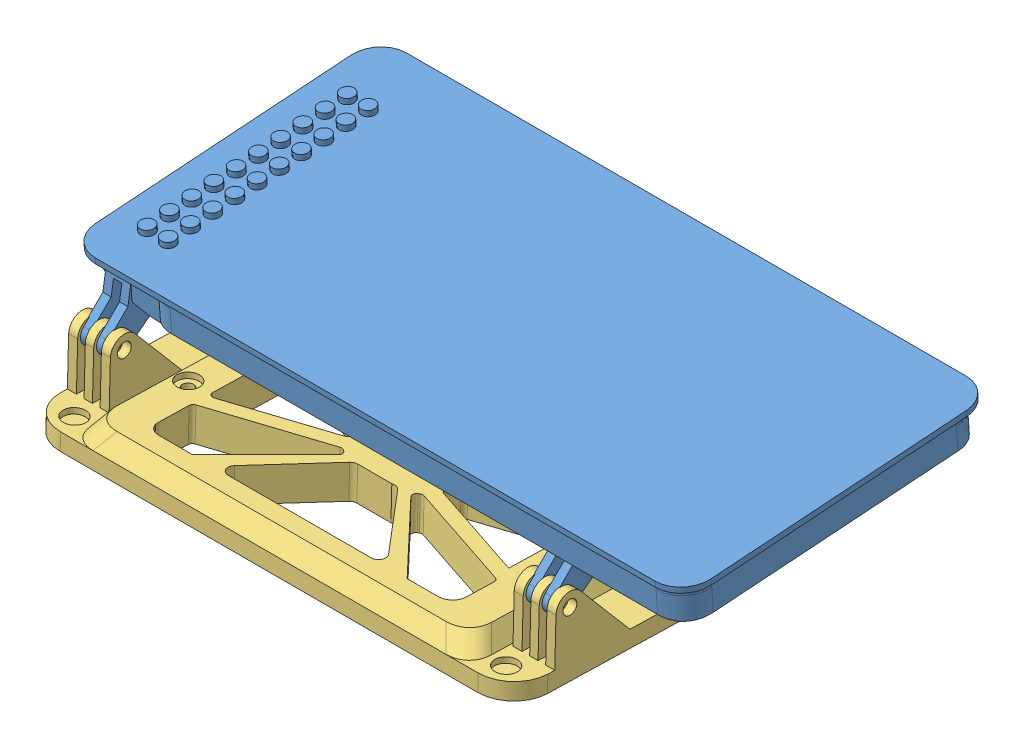
SolidWorks assembly Pi Screen Assembly, configuration Default. Lengths in mm.
Overall size (221 61.76 131.08).
3 component instances, 3 part files, 7 mates.
Components (placement in the parent):
- Pi Touch Screen-1: Pi Touch Screen [Default] at (61.75 84.4571 107.2044) x (1 0 0) z (0 0.997511 0.070505) size (221 114.52 33.01)
- User Library-Raspberry Pi 3-2-1: User Library-Raspberry Pi 3-2 [Default] at (-18.5338 72.6927 106.2834) x (-1 0 0) z (0 -0.997511 -0.070505) size (89.64 57.31 18.59)
- Raspberry Pi case-1: Raspberry Pi case [Default] at (29.5 34.9078 131.6046) x (1 0 0) z (0 0.999657 -0.026177) size (175 98 28)
Mates (geometry in assembly coordinates):
- Concentric1: concentric anti-aligned: cylinder of Pi Touch Screen-1 through (26.4082 73.3931 79.355) axis (0 0.997511 0.070505) radius 1.375; cylinder of User Library-Raspberry Pi 3-2-1 through (26.4082 75.3382 79.4925) axis (0 -0.997511 -0.070505) radius 1.375
- Concentric2: concentric anti-aligned: cylinder of Pi Touch Screen-1 through (-31.5918 69.9383 128.2331) axis (0 0.997511 0.070505) radius 1.375; cylinder of User Library-Raspberry Pi 3-2-1 through (-31.5918 71.8835 128.3706) axis (0 -0.997511 -0.070505) radius 1.375
- Coincident1: coincident aligned: plane of Pi Touch Screen-1 through (26.4082 69.9383 128.2331) normal (0 -0.997511 -0.070505); plane of User Library-Raspberry Pi 3-2-1 through (29.5182 69.719 131.3353) normal (0 -0.997511 -0.070505)
- Coincident6: coincident anti-aligned: plane of Pi Touch Screen-1 through (111 58.6602 160.0359) normal (-1 0 0); plane of Raspberry Pi case-1 through (111 63.7894 164.9033) normal (1 0 0)
- Coincident7: coincident anti-aligned: plane of Pi Touch Screen-1 through (-52 58.6602 160.0359) normal (1 0 0); plane of Raspberry Pi case-1 through (-52 63.7894 164.9033) normal (-1 0 0)
- Concentric3: concentric aligned: cylinder of Pi Touch Screen-1 through (105 58.6602 160.0359) axis (1 0 0) radius 2.5; cylinder of Raspberry Pi case-1 through (102 58.6602 160.0359) axis (1 0 0) radius 2.5
- Concentric4: concentric aligned: cylinder of Pi Touch Screen-1 through (-46 58.6602 160.0359) axis (-1 0 0) radius 2.5; cylinder of Raspberry Pi case-1 through (-43 58.6602 160.0359) axis (-1 0 0) radius 2.5
